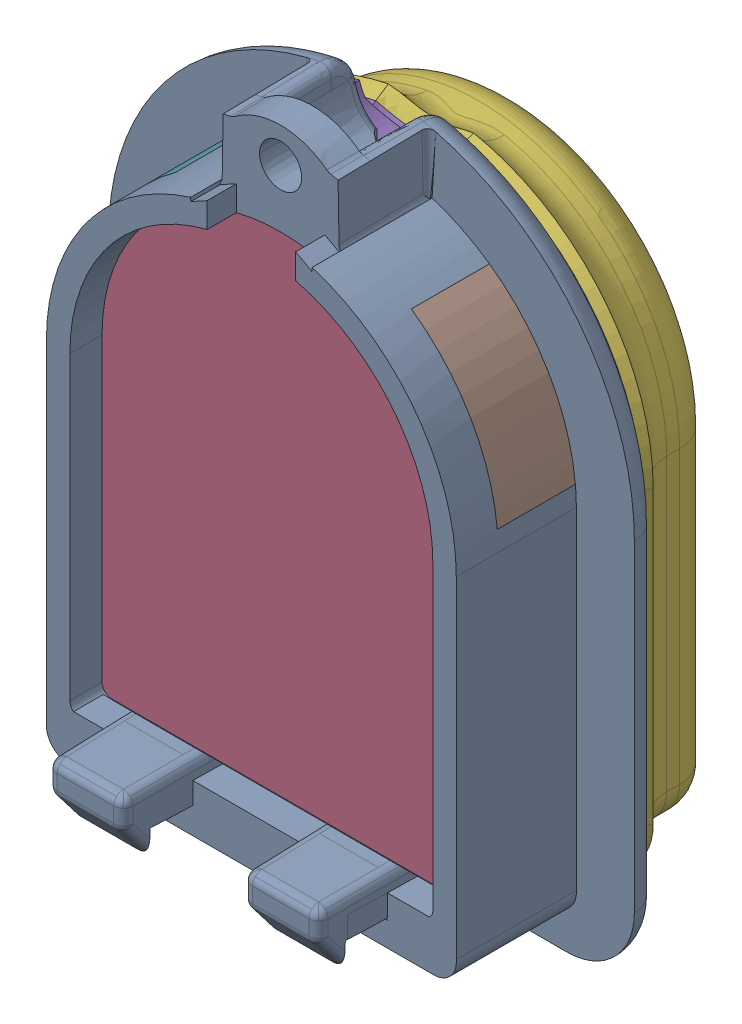
SolidWorks assembly PinDesign_1, configuration 默认. Lengths in mm.
Overall size (26.95 34.26 16.36).
9 component instances, 8 part files, 24 mates.
Components (placement in the parent):
- Pin1Tip1-1: Pin1Tip1 [默认] at (-1.9035 7.7463 -5.5591) size (26.95 34.26 11.2)
- Pin1lensnew-1: Pin1lensnew [默认] at (-1.9035 7.7463 -5.5591) size (18.6 25.2 6)
- Pin1Skin0.2-1: Pin1Skin0.2 [默认] at (-1.9035 7.4963 -5.5591) x (-1 0 0) z (0 0 -1) size (23.9 30.06 5.2)
- Pin1Skin1-1: Pin1Skin1 [默认] at (-1.9035 7.4963 -5.5591) x (-1 0 0) z (0 0 -1) size (22.77 29.32 5.25) (hidden)
- Pin1sidelens1-1: Pin1sidelens1 [默认] at (-1.9035 7.7463 -6.2091) size (6.4 7.71 4)
- Pin1sidelens1-2: Pin1sidelens1 [默认] at (-1.9035 7.7463 2.0909) x (-1 0 0) z (0 0 -1) size (6.4 7.71 4)
- Pin1bottomlens-1: Pin1bottomlens [默认] at (-5.9035 -10.5037 0.4409) x (1 0 0) z (0 1 0) size (8 4.5 2.35)
- Pin1PinMarker_1mm-1: Pin1PinMarker_1mm [默认] at (5.5965 8.9053 -9.7591) x (0 -1 0) z (0 0 -1) size (22.14 16.14 1)
- Pin1MarkerTIp-1: Pin1MarkerTIp [默认] at (-1.9035 4.4053 -9.7591) x (0 1 0) z (0 0 1) size (22 16 0.4)
Mates (geometry in assembly coordinates):
- 同心1: concentric aligned: cylinder of Tip1-1 through (-1.9035 7.7463 51.2878) axis (0 0 -1) radius 9.3; cylinder of lensnew-1 through (-1.9035 7.7463 0.4409) axis (0 0 -1) radius 9.3
- 重合1: coincident anti-aligned: plane of Tip1-1 through (-1.9035 -8.1537 51.2878) normal (0 1 0); plane of lensnew-1 through (-11.2035 -8.1537 0.4409) normal (0 -1 0)
- 重合2: coincident aligned: plane of Tip1-1 through (-1.964 4.3089 -5.5591) normal (0 0 -1); plane of lensnew-1 through (-1.9035 7.7463 -5.5591) normal (0 0 -1)
- 重合3: coincident anti-aligned: plane of lensnew-1 through (-1.9035 7.7463 -5.5591) normal (0 0 -1); plane of Skin0.2-1 through (-1.9035 7.4963 -5.5591) normal (0 0 1)
- 同心2: concentric aligned: cone of Tip1-1 through (-1.9035 19.9963 -1.0591) axis (0 0 1); cylinder of Skin0.2-1 through (-1.9035 19.9963 -6.3091) axis (0 0 1) radius 2.75
- 宽度1: width aligned: plane of Skin0.2-1 through (-13.8535 7.4963 -5.5591) normal (-1 0 0); plane of Skin0.2-1 through (10.0465 7.4963 -5.5591) normal (1 0 0); plane of Tip1-1 through (-12.4035 7.7463 2.0909) normal (-1 0 0); plane of Tip1-1 through (8.5965 7.7463 2.0909) normal (1 0 0)
- 重合4: coincident anti-aligned: plane of Skin0.2-1 through (-1.9035 7.4963 -10.7591) normal (0 0 -1); plane of Skin1-1 through (-1.9035 7.4963 -10.7591) normal (0 0 1)
- 宽度2: width anti-aligned: plane of Skin0.2-1 through (-13.8535 7.4963 -5.5591) normal (-1 0 0); plane of Skin0.2-1 through (10.0465 7.4963 -5.5591) normal (1 0 0); plane of Skin1-1 through (-12.8325 0.0508 -6.2245) normal (-0.891007 0 0.45399); plane of Skin1-1 through (9.0255 0.0508 -6.2245) normal (0.891007 0 0.45399)
- 重合5: coincident aligned: cone of Skin0.2-1 through (-1.9035 7.4963 -6.2245) axis (0 0 1); cone of Skin1-1 through (-1.9035 7.4963 -6.2245) axis (0 0 1)
- 重合6: coincident anti-aligned: plane of Tip1-1 through (-16.7251 9.2061 -4.0591) normal (0.104528 0.994522 0); plane of sidelens1-1 through (8.4147 6.5638 -0.0591) normal (-0.104528 -0.994522 0)
- 重合7: coincident anti-aligned: plane of Tip1-1 through (-1.9035 7.7463 -4.0591) normal (0 0 1); plane of sidelens1-1 through (8.4147 6.5638 -4.0591) normal (0 0 -1)
- 同心3: concentric aligned: cylinder of Tip1-1 through (-1.9035 7.7463 2.0909) axis (0 0 -1) radius 10.5; cylinder of sidelens1-1 through (-1.9035 7.7463 -0.0591) axis (0 0 -1) radius 10.5
- 同心4: concentric anti-aligned: cylinder of Tip1-1 through (-1.9035 7.7463 2.0909) axis (0 0 -1) radius 10.5; cylinder of sidelens1-2 through (-1.9035 7.7463 -4.0591) axis (0 0 1) radius 10.5
- 重合8: coincident anti-aligned: plane of Tip1-1 through (12.0819 17.1622 -0.0591) normal (0.104528 -0.994522 0); plane of sidelens1-2 through (-13.0579 14.5199 -4.0591) normal (-0.104528 0.994522 0)
- 重合9: coincident anti-aligned: plane of Tip1-1 through (-1.9035 7.7463 -4.0591) normal (0 0 1); plane of sidelens1-2 through (-1.9035 7.7463 -4.0591) normal (0 0 -1)
- 重合10: coincident anti-aligned: plane of lensnew-1 through (-11.2035 -8.1537 0.4409) normal (0 -1 0); plane of bottomlens-1 through (-5.9035 -8.1537 0.4409) normal (0 1 0)
- 重合11: coincident anti-aligned: plane of Tip1-1 through (-5.9035 -18.1537 0.4409) normal (0 0 -1); plane of bottomlens-1 through (-5.9035 -8.1537 0.4409) normal (0 0 1)
- 重合12: coincident anti-aligned: plane of Tip1-1 through (2.0965 -18.1537 0.4409) normal (-1 0 0); plane of bottomlens-1 through (2.0965 -8.1537 0.4409) normal (1 0 0)
- 重合13: coincident aligned: plane of Skin0.2-1 through (-1.9035 7.4963 -10.7591) normal (0 0 -1); plane of PinMarker_1mm-1 through (-3.4035 2.9053 -10.7591) normal (0 0 -1)
- 对称1: symmetric aligned: plane of Tip1-1 through (8.5965 7.7463 2.0909) normal (1 0 0); plane of Tip1-1 through (-12.4035 7.7463 2.0909) normal (-1 0 0); plane of PinMarker_1mm-1 through (-1.9035 8.9053 -9.7591) normal (-1 0 0)
- 距离1: distance = 10 mm aligned: plane of Skin0.2-1 through (7.3875 -8.5947 -5.5591) normal (0 -1 0); plane of PinMarker_1mm-1 through (5.5965 1.4053 -9.7591) normal (0 -1 0)
- 同心5: concentric anti-aligned: cone of PinMarker_1mm-1 through (-0.4035 14.9053 -9.7591) axis (0 0 1); cylinder of MarkerTIp-1 through (-0.4035 14.9053 -9.3591) axis (0 0 -1) radius 0.5
- 同心6: concentric anti-aligned: cone of PinMarker_1mm-1 through (-3.4035 14.9053 -9.7591) axis (0 0 1); cylinder of MarkerTIp-1 through (-3.4035 14.9053 -9.3591) axis (0 0 -1) radius 0.5
- 重合14: coincident anti-aligned: plane of PinMarker_1mm-1 through (-0.4035 14.9053 -9.7591) normal (0 0 1); plane of MarkerTIp-1 through (-1.9035 4.4053 -9.7591) normal (0 0 -1)
